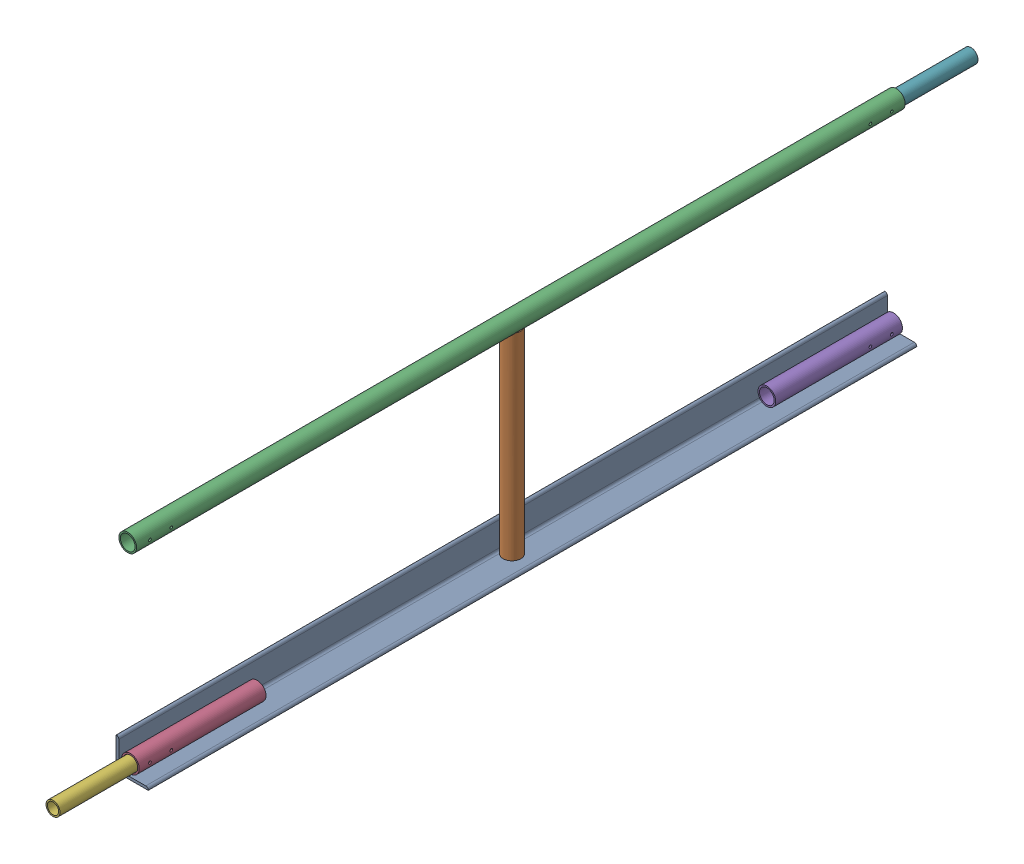
SolidWorks assembly FE-00022_ASM, configuration Default. Lengths in mm.
Overall size (76.2 507.65 2184.4).
8 component instances, 5 part files, 0 mates.
Components (placement in the parent):
- FE-00005_ASM-1: FE-00005_ASM [Default] at origin size (76.2 507.65 1828.8)
  - FE-00005-01-1: FE-00005-01 [Default] at origin size (76.2 76.2 1828.8)
  - FE-00005-03-1: FE-00005-03 [Default] at (27.432 6.35 914.4) size (42.16 471.23 42.16)
  - FE-00005-04-1: FE-00005-04 [Default] at (27.432 486.5688 0) size (42.16 42.16 1828.8)
  - FE-00005-02-1: FE-00005-02 [Default] at (27.432 27.432 1520.825) size (42.16 42.16 301.62)
  - FE-00005-02-2: FE-00005-02 [Default] at (27.432 27.432 307.975) x (1 0 0) z (0 0 -1) size (42.16 42.16 301.62)
- FE-00026-1: FE-00026 [Default] at (27.432 27.432 1651) size (33.4 33.4 355.6)
- FE-00026-2: FE-00026 [Default] at (27.432 486.5688 177.8) x (-1 0 0) z (0 0 -1) size (33.4 33.4 355.6)
